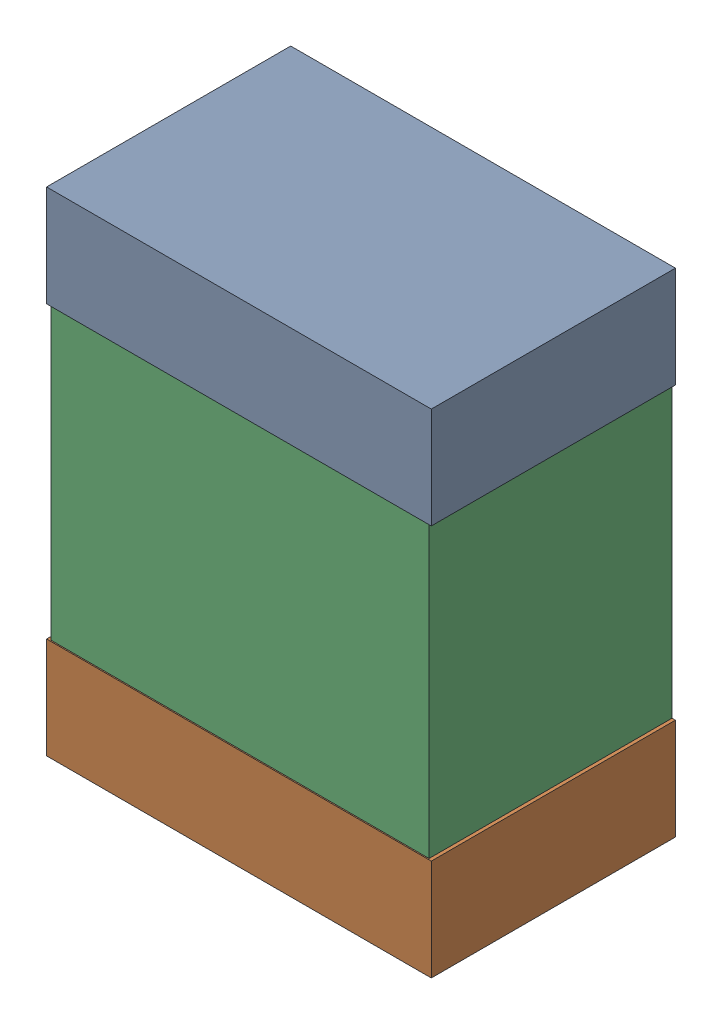
SolidWorks assembly CinB3Kanaloa_v2.0.0_Power, configuration Default. Lengths in mm.
Overall size (2.85 3.65 1.81).
6 component instances, 2 part files, 0 mates.
Components (placement in the parent):
- 334789552-1: 334789552 [Default] at (59 81.925 0) size (2.85 0.75 1.81)
  - Extruded_9-1: Extruded_9 [Default] at origin size (2.85 0.75 1.81)
- 334789552-2: 334789552 [Default] at (59 79.025 0) size (2.85 0.75 1.81)
  - Extruded_9-1: Extruded_9 [Default] at origin size (2.85 0.75 1.81)
- 334789424-1: 334789424 [Default] at (59 80.475 0) size (2.8 3.6 1.8)
  - Extruded_10-1: Extruded_10 [Default] at origin size (2.8 3.6 1.8)
